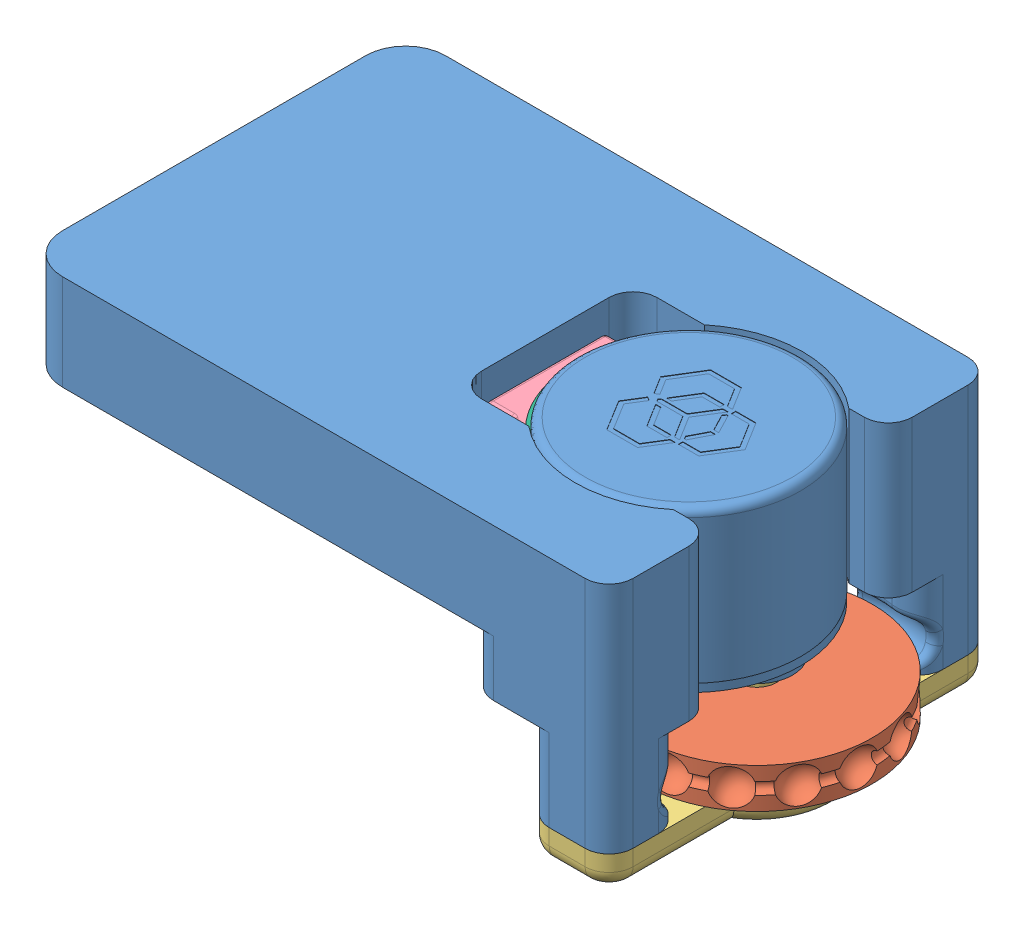
SolidWorks assembly Full AssmeblyV2, configuration Default. Lengths in mm.
Overall size (87.84 33.3 48).
138 component instances, 75 part files, 10 mates.
Components (placement in the parent):
- CaseBotV2-1: CaseBotV2 [Default] at (-9.6674 5.3803 5.897) size (73.5 29.35 48)
- ULN2003 Stepper Driver-1: ULN2003 Stepper Driver [Default] at (-30.6167 -11.0165 22.2166) x (1 0 0) z (0 -1 0) size (31 35 20)
  - pcb_1-1: pcb_1 [Default] at origin size (31 35 1.6)
  - jumper_connector-1: jumper_connector [Default] at (-15.35 -12.425 0) size (2 5 6)
    - jumper_connector_1_2-1: jumper_connector_1_2 [Default] at origin size (2 5 6)
    - jumper_connector_1-1: jumper_connector_1 [Default] at origin size (1.2 3.8 1)
  - r205-1: r205 [Default] at (-15.3 -2.6 0) size (6.69 1.8 3.9)
    - r205_1_3-1: r205_1_3 [Default] at origin size (2.6 0.2 3.1)
    - r205_1-1: r205_1 [Default] at origin size (2.6 0.2 3.1)
    - r205_1_2-1: r205_1_2 [Default] at origin size (3.6 1.8 1.8)
  - r205-2: r205 [Default] at (-15.3 -5.14 0) size (6.69 1.8 3.9)
    - r205_1_3-1: r205_1_3 [Default] at origin size (2.6 0.2 3.1)
    - r205_1-1: r205_1 [Default] at origin size (2.6 0.2 3.1)
    - r205_1_2-1: r205_1_2 [Default] at origin size (3.6 1.8 1.8)
  - r205-3: r205 [Default] at (-15.3 -7.68 0) size (6.69 1.8 3.9)
    - r205_1_3-1: r205_1_3 [Default] at origin size (2.6 0.2 3.1)
    - r205_1-1: r205_1 [Default] at origin size (2.6 0.2 3.1)
    - r205_1_2-1: r205_1_2 [Default] at origin size (3.6 1.8 1.8)
  - r205-4: r205 [Default] at (-15.3 -10.22 0) size (6.69 1.8 3.9)
    - r205_1_3-1: r205_1_3 [Default] at origin size (2.6 0.2 3.1)
    - r205_1-1: r205_1 [Default] at origin size (2.6 0.2 3.1)
    - r205_1_2-1: r205_1_2 [Default] at origin size (3.6 1.8 1.8)
  - motor_connector-1: motor_connector [Default] at (-15.5 -17.5 0.2) size (15 5.5 9.89)
    - motor_connector_1-1: motor_connector_1 [Default] at origin size (15 5.5 7)
    - conn_lead_1-1: conn_lead_1 [Default] at origin size (0.4 0.4 8.89)
    - conn_lead_1-2: conn_lead_1 [Default] at (-2.54 0 0) size (0.4 0.4 8.89)
    - conn_lead_1-3: conn_lead_1 [Default] at (-5.08 0 0) size (0.4 0.4 8.89)
    - conn_lead_1-4: conn_lead_1 [Default] at (-7.62 0 0) size (0.4 0.4 8.89)
    - conn_lead_1-5: conn_lead_1 [Default] at (-10.16 0 0) size (0.4 0.4 8.89)
  - Pin Header 1x4 TH Pitch 2.54mm v2-1: Pin Header 1x4 TH Pitch 2.54mm v2 [Default] at (9.1801 10.9799 0) x (-1 0 0) z (0 0 -1) size (10.16 2.58 11.43)
    - asm_pin-1: asm_pin [Default] at origin size (2.54 2.58 11.43)
      - spacer_1-1: spacer_1 [Default] at origin size (2.54 2.58 2.54)
      - pin_1-1: pin_1 [Default] at origin size (0.64 0.64 11.43)
    - asm_pin_1-1: asm_pin_1 [Default] at (2.54 0 0) size (2.54 2.58 11.43)
      - spacer_1-1: spacer_1 [Default] at origin size (2.54 2.58 2.54)
      - pin_1-1: pin_1 [Default] at origin size (0.64 0.64 11.43)
    - asm_pin_2-1: asm_pin_2 [Default] at (5.08 0 0) size (2.54 2.58 11.43)
      - spacer_1-1: spacer_1 [Default] at origin size (2.54 2.58 2.54)
      - pin_1-1: pin_1 [Default] at origin size (0.64 0.64 11.43)
    - asm_pin_3-1: asm_pin_3 [Default] at (7.62 0 0) size (2.54 2.58 11.43)
      - spacer_1-1: spacer_1 [Default] at origin size (2.54 2.58 2.54)
      - pin_1-1: pin_1 [Default] at origin size (0.64 0.64 11.43)
  - Pin Header 1x4 TH Pitch 2.54mm v2 (1)-1: Pin Header 1x4 TH Pitch 2.54mm v2 (1) [Default] at (-10.4999 8.0001 1.5722) x (0 -1 0) z (0 0 1) size (10.16 2.58 11.43)
    - asm_pin (1)-1: asm_pin (1) [Default] at origin size (2.54 2.58 11.43)
      - spacer (1)_1-1: spacer (1)_1 [Default] at origin size (2.54 2.58 2.54)
      - pin (1)_1-1: pin (1)_1 [Default] at origin size (0.64 0.64 11.43)
    - asm_pin (1)_1-1: asm_pin (1)_1 [Default] at (2.54 0 0) size (2.54 2.58 11.43)
      - spacer (1)_1-1: spacer (1)_1 [Default] at origin size (2.54 2.58 2.54)
      - pin (1)_1-1: pin (1)_1 [Default] at origin size (0.64 0.64 11.43)
    - asm_pin (1)_2-1: asm_pin (1)_2 [Default] at (5.08 0 0) size (2.54 2.58 11.43)
      - spacer (1)_1-1: spacer (1)_1 [Default] at origin size (2.54 2.58 2.54)
      - pin (1)_1-1: pin (1)_1 [Default] at origin size (0.64 0.64 11.43)
    - asm_pin (1)_3-1: asm_pin (1)_3 [Default] at (7.62 0 0) size (2.54 2.58 11.43)
      - spacer (1)_1-1: spacer (1)_1 [Default] at origin size (2.54 2.58 2.54)
      - pin (1)_1-1: pin (1)_1 [Default] at origin size (0.64 0.64 11.43)
  - LED 3mm-1: LED 3mm [Default] at (-3.9107 -12.6768 1.7661) x (0 -1 0) z (-1 0 0) size (3.33 7.5 3.5)
    - LED 3mm_1_3-1: LED 3mm_1_3 [Default] at origin size (3.33 5.5 3.5)
    - LED 3mm_1-1: LED 3mm_1 [Default] at origin size (1.37 4.28 0.64)
    - LED 3mm_1_2-1: LED 3mm_1_2 [Default] at origin size (1.1 4.25 0.3)
  - LED 3mm-2: LED 3mm [Default] at (0.5893 -12.6768 1.7661) x (0 -1 0) z (-1 0 0) size (3.33 7.5 3.5)
    - LED 3mm_1_3-1: LED 3mm_1_3 [Default] at origin size (3.33 5.5 3.5)
    - LED 3mm_1-1: LED 3mm_1 [Default] at origin size (1.37 4.28 0.64)
    - LED 3mm_1_2-1: LED 3mm_1_2 [Default] at origin size (1.1 4.25 0.3)
  - LED 3mm-3: LED 3mm [Default] at (5.0893 -12.6768 1.7661) x (0 -1 0) z (-1 0 0) size (3.33 7.5 3.5)
    - LED 3mm_1_3-1: LED 3mm_1_3 [Default] at origin size (3.33 5.5 3.5)
    - LED 3mm_1-1: LED 3mm_1 [Default] at origin size (1.37 4.28 0.64)
    - LED 3mm_1_2-1: LED 3mm_1_2 [Default] at origin size (1.1 4.25 0.3)
  - LED 3mm-4: LED 3mm [Default] at (9.5893 -12.6768 1.7661) x (0 -1 0) z (-1 0 0) size (3.33 7.5 3.5)
    - LED 3mm_1_3-1: LED 3mm_1_3 [Default] at origin size (3.33 5.5 3.5)
    - LED 3mm_1-1: LED 3mm_1 [Default] at origin size (1.37 4.28 0.64)
    - LED 3mm_1_2-1: LED 3mm_1_2 [Default] at origin size (1.1 4.25 0.3)
  - dip16 v2-1: dip16 v2 [Default] at (4.1 3.5 6) x (0 1 0) z (0 0 1) size (8.74 20 8.41)
    - package_1-1: package_1 [Default] at origin size (7.1 20 4.6)
    - lead-1: lead [Default] at origin size (8.74 18.4 6.23)
      - lead_1_7-1: lead_1_7 [Default] at origin size (0.97 1.35 6.23)
      - lead_1_12-1: lead_1_12 [Default] at origin size (0.97 0.99 6.23)
      - lead_1_14-1: lead_1_14 [Default] at origin size (0.97 1.35 6.23)
      - lead_1_8-1: lead_1_8 [Default] at origin size (0.97 1.35 6.23)
      - lead_1_2-1: lead_1_2 [Default] at origin size (0.97 1.35 6.23)
      - lead_1_5-1: lead_1_5 [Default] at origin size (0.97 1.35 6.23)
      - lead_1_10-1: lead_1_10 [Default] at origin size (0.97 1.35 6.23)
      - lead_1_4-1: lead_1_4 [Default] at origin size (0.97 0.99 6.23)
      - lead_1_9-1: lead_1_9 [Default] at origin size (0.97 1.35 6.23)
      - lead_1_11-1: lead_1_11 [Default] at origin size (0.97 0.99 6.23)
      - lead_1-1: lead_1 [Default] at origin size (0.97 1.35 6.23)
      - lead_1_13-1: lead_1_13 [Default] at origin size (0.97 1.35 6.23)
      - lead_1_3-1: lead_1_3 [Default] at origin size (0.97 1.35 6.23)
      - lead_1_16-1: lead_1_16 [Default] at origin size (0.97 1.35 6.23)
      - lead_1_6-1: lead_1_6 [Default] at origin size (0.97 1.35 6.23)
      - lead_1_15-1: lead_1_15 [Default] at origin size (0.97 0.99 6.23)
  - dip16_socket v4-1: dip16_socket v4 [Default] at (4.1 3.7 1.6) x (-1 0 0) z (0 0 1) size (20.49 10.21 8.2)
    - housing_1-1: housing_1 [Default] at origin size (20.49 10.21 5.04)
    - pins-1: pins [Default] at origin size (19.03 9.24 7.72)
      - pins_1_15-1: pins_1_15 [Default] at origin size (1.25 2.92 7.72)
      - pins_1_6-1: pins_1_6 [Default] at origin size (1.25 2.92 7.72)
      - pins_1_11-1: pins_1_11 [Default] at origin size (1.25 2.92 7.72)
      - pins_1-1: pins_1 [Default] at origin size (1.25 2.92 7.72)
      - pins_1_14-1: pins_1_14 [Default] at origin size (1.25 2.92 7.72)
      - pins_1_8-1: pins_1_8 [Default] at origin size (1.25 2.92 7.72)
      - pins_1_12-1: pins_1_12 [Default] at origin size (1.25 2.92 7.72)
      - pins_1_9-1: pins_1_9 [Default] at origin size (1.25 2.92 7.72)
      - pins_1_7-1: pins_1_7 [Default] at origin size (1.25 2.92 7.72)
      - pins_1_4-1: pins_1_4 [Default] at origin size (1.25 2.92 7.72)
      - pins_1_3-1: pins_1_3 [Default] at origin size (1.25 2.92 7.72)
      - pins_1_13-1: pins_1_13 [Default] at origin size (1.25 2.92 7.72)
      - pins_1_10-1: pins_1_10 [Default] at origin size (1.25 2.92 7.72)
      - pins_1_5-1: pins_1_5 [Default] at origin size (1.25 2.92 7.72)
      - pins_1_2-1: pins_1_2 [Default] at origin size (1.25 2.92 7.72)
      - pins_1_16-1: pins_1_16 [Default] at origin size (1.25 2.92 7.72)
- ESP8266-12-Mini Node-1: ESP8266-12-Mini Node [Default] at (-28.7704 1.7047 18.5075) size (32 7.19 26.5)
  - BotPCB-1: BotPCB [Default] at (2.3558 -7.7212 3.459) size (32 1.6 26.5)
  - ESP-12F-1: ESP-12F [Default] at (6.1537 -6.1212 3.209) x (0 0 1) z (0 1 0) size (16 24 2.96)
  - micro_USB-1: micro_USB [Default] at (-29.1048 -15.4181 18.5431) x (0 0 1) z (-1 0 0) size (7.97 2.92 5.43)
    - raspberry_pi_B+_(micro_USB_cover)-1: raspberry_pi_B+_(micro_USB_cover) [Default] at (-14.4796 6.4719 -16.0085) size (7.97 2.92 5.43)
    - raspberry_pi_B+_(micro_USB_contacts)-1: raspberry_pi_B+_(micro_USB_contacts) [Default] at (-14.4796 6.4719 -20.7085) size (6.9 2.16 4.2)
- MotorAndGearV2-1: MotorAndGearV2 [Default] at (6.5382 -11.1474 19.8614) x (0 0 1) z (-1 0 0) size (43 33.3 55.34)
  - StepMotor28BYJ-48-1: StepMotor28BYJ-48 [Default] at (-1.1449 -8.3691 -3.845) size (43 29.3 41)
    - Øàãîâûé äâèãàòåëü ñ ïëàòîé óïðàâëåíèÿ (äâèãàòåëü)_8-1: Øàãîâûé äâèãàòåëü ñ ïëàòîé óïðàâëåíèÿ (äâèãàòåëü)_8 [Default] at origin size (43 2.5 30)
    - Øàãîâûé äâèãàòåëü ñ ïëàòîé óïðàâëåíèÿ (äâèãàòåëü)_15-1: Øàãîâûé äâèãàòåëü ñ ïëàòîé óïðàâëåíèÿ (äâèãàòåëü)_15 [Default] at origin size (7 1.3 7)
    - Øàãîâûé äâèãàòåëü ñ ïëàòîé óïðàâëåíèÿ (äâèãàòåëü)_4-1: Øàãîâûé äâèãàòåëü ñ ïëàòîé óïðàâëåíèÿ (äâèãàòåëü)_4 [Default] at origin size (5 8 5)
    - Øàãîâûé äâèãàòåëü ñ ïëàòîé óïðàâëåíèÿ (äâèãàòåëü)-1: Øàãîâûé äâèãàòåëü ñ ïëàòîé óïðàâëåíèÿ (äâèãàòåëü) [Default] at origin size (21 12.5 8.74)
    - Øàãîâûé äâèãàòåëü ñ ïëàòîé óïðàâëåíèÿ (äâèãàòåëü)_17-1: Øàãîâûé äâèãàòåëü ñ ïëàòîé óïðàâëåíèÿ (äâèãàòåëü)_17 [Default] at origin size (9 2 5.16)
    - Øàãîâûé äâèãàòåëü ñ ïëàòîé óïðàâëåíèÿ (äâèãàòåëü)_14-1: Øàãîâûé äâèãàòåëü ñ ïëàòîé óïðàâëåíèÿ (äâèãàòåëü)_14 [Default] at origin size (9 2 5.16)
    - Øàãîâûé äâèãàòåëü ñ ïëàòîé óïðàâëåíèÿ (äâèãàòåëü)_5-1: Øàãîâûé äâèãàòåëü ñ ïëàòîé óïðàâëåíèÿ (äâèãàòåëü)_5 [Default] at origin size (15 4 6.18)
    - Øàãîâûé äâèãàòåëü ñ ïëàòîé óïðàâëåíèÿ (äâèãàòåëü)_7-1: Øàãîâûé äâèãàòåëü ñ ïëàòîé óïðàâëåíèÿ (äâèãàòåëü)_7 [Default] at origin size (13 3 3.6)
    - Øàãîâûé äâèãàòåëü ñ ïëàòîé óïðàâëåíèÿ (äâèãàòåëü)_2-1: Øàãîâûé äâèãàòåëü ñ ïëàòîé óïðàâëåíèÿ (äâèãàòåëü)_2 [Default] at origin size (0.9 0.9 10)
    - Øàãîâûé äâèãàòåëü ñ ïëàòîé óïðàâëåíèÿ (äâèãàòåëü)_6-1: Øàãîâûé äâèãàòåëü ñ ïëàòîé óïðàâëåíèÿ (äâèãàòåëü)_6 [Default] at origin size (0.9 0.9 10)
    - Øàãîâûé äâèãàòåëü ñ ïëàòîé óïðàâëåíèÿ (äâèãàòåëü)_16-1: Øàãîâûé äâèãàòåëü ñ ïëàòîé óïðàâëåíèÿ (äâèãàòåëü)_16 [Default] at origin size (0.9 0.9 10)
    - Øàãîâûé äâèãàòåëü ñ ïëàòîé óïðàâëåíèÿ (äâèãàòåëü)_12-1: Øàãîâûé äâèãàòåëü ñ ïëàòîé óïðàâëåíèÿ (äâèãàòåëü)_12 [Default] at origin size (0.9 0.9 10)
    - Øàãîâûé äâèãàòåëü ñ ïëàòîé óïðàâëåíèÿ (äâèãàòåëü)_18-1: Øàãîâûé äâèãàòåëü ñ ïëàòîé óïðàâëåíèÿ (äâèãàòåëü)_18 [Default] at origin size (0.9 0.9 10)
    - Øàãîâûé äâèãàòåëü ñ ïëàòîé óïðàâëåíèÿ (äâèãàòåëü)_9-1: Øàãîâûé äâèãàòåëü ñ ïëàòîé óïðàâëåíèÿ (äâèãàòåëü)_9 [Default] at origin size (0.45 0.45 2)
    - Øàãîâûé äâèãàòåëü ñ ïëàòîé óïðàâëåíèÿ (äâèãàòåëü)_11-1: Øàãîâûé äâèãàòåëü ñ ïëàòîé óïðàâëåíèÿ (äâèãàòåëü)_11 [Default] at origin size (0.45 0.45 2)
    - Øàãîâûé äâèãàòåëü ñ ïëàòîé óïðàâëåíèÿ (äâèãàòåëü)_13-1: Øàãîâûé äâèãàòåëü ñ ïëàòîé óïðàâëåíèÿ (äâèãàòåëü)_13 [Default] at origin size (0.45 0.45 2)
    - Øàãîâûé äâèãàòåëü ñ ïëàòîé óïðàâëåíèÿ (äâèãàòåëü)_19-1: Øàãîâûé äâèãàòåëü ñ ïëàòîé óïðàâëåíèÿ (äâèãàòåëü)_19 [Default] at origin size (0.45 0.45 2)
    - Øàãîâûé äâèãàòåëü ñ ïëàòîé óïðàâëåíèÿ (äâèãàòåëü)_3-1: Øàãîâûé äâèãàòåëü ñ ïëàòîé óïðàâëåíèÿ (äâèãàòåëü)_3 [Default] at origin size (0.45 0.45 2)
    - Øàãîâûé äâèãàòåëü ñ ïëàòîé óïðàâëåíèÿ (äâèãàòåëü)_10-1: Øàãîâûé äâèãàòåëü ñ ïëàòîé óïðàâëåíèÿ (äâèãàòåëü)_10 [Default] at origin size (28 19 28)
  - Gear1-1: Gear1 [Default] at (-1.1449 -16.6691 -12.345) x (-0.866025 0 0.5) z (0 1 0) size (29.06 29.01 10)
- topBar-1: topBar [Default] at (19.1333 -32.8165 18.7166) size (20 4 48)
Mates (geometry in assembly coordinates):
- Coincident1: coincident anti-aligned: plane of CaseBotV2-1 through (-26.4146 -4.4165 21.9666) normal (0 -1 0); plane of ESP8266-12-Mini Node-1/BotPCB-1 through (-26.4146 -4.4165 21.9666) normal (0 1 0)
- Coincident3: coincident anti-aligned: plane of CaseBotV2-1 through (-9.6674 -11.0165 5.897) normal (0 -1 0); plane of ULN2003 Stepper Driver-1/pcb_1-1 through (-30.6167 -11.0165 22.2166) normal (0 1 0)
- Concentric4: concentric anti-aligned: cylinder of ULN2003 Stepper Driver-1/pcb_1-1 through (-44.1167 -12.6165 7.2166) axis (0 1 0) radius 1.4; circle of CaseBotV2-1
- Parallel1: parallel aligned: plane of CaseBotV2-1 through (-7.6167 0.4835 5.897) normal (1 0 0); plane of ? through (-7.6167 -3.0165 25.7166) normal (1 0 0)
- Parallel2: parallel aligned: plane of CaseBotV2-1 through (-9.6674 0.4835 5.897) normal (0 1 0); plane of ? through (10.3833 0.4835 18.7166) normal (0 1 0)
- Coincident6: coincident aligned: plane of CaseBotV2-1 through (-9.6674 0.4835 5.897) normal (0 1 0); plane of ? through (10.3833 0.4835 18.7166) normal (0 1 0)
- Coincident7: coincident aligned: plane of CaseBotV2-1 through (-7.6167 0.4835 5.897) normal (1 0 0); plane of ? through (-7.6167 -3.0165 25.7166) normal (1 0 0)
- Coincident8: coincident anti-aligned: plane of CaseBotV2-1 through (-9.6674 5.3803 18.7166) normal (0 0 -1); plane of ? through (10.3833 -19.5165 18.7166) normal (0 0 1)
- Concentric6: concentric anti-aligned: cylinder of MotorAndGearV2-1/Gear1-1 through (18.8833 -32.8165 18.7166) axis (0 1 0) radius 3.75; cylinder of topBar-1 through (18.8833 -28.8165 18.7166) axis (0 -1 0) radius 4
- Coincident9: coincident anti-aligned: line of CaseBotV2-1 through (21.3833 -28.8165 42.7166) axis (-1 0 0); line of topBar-1 through (16.8833 -28.8165 42.7166) axis (1 0 0)
